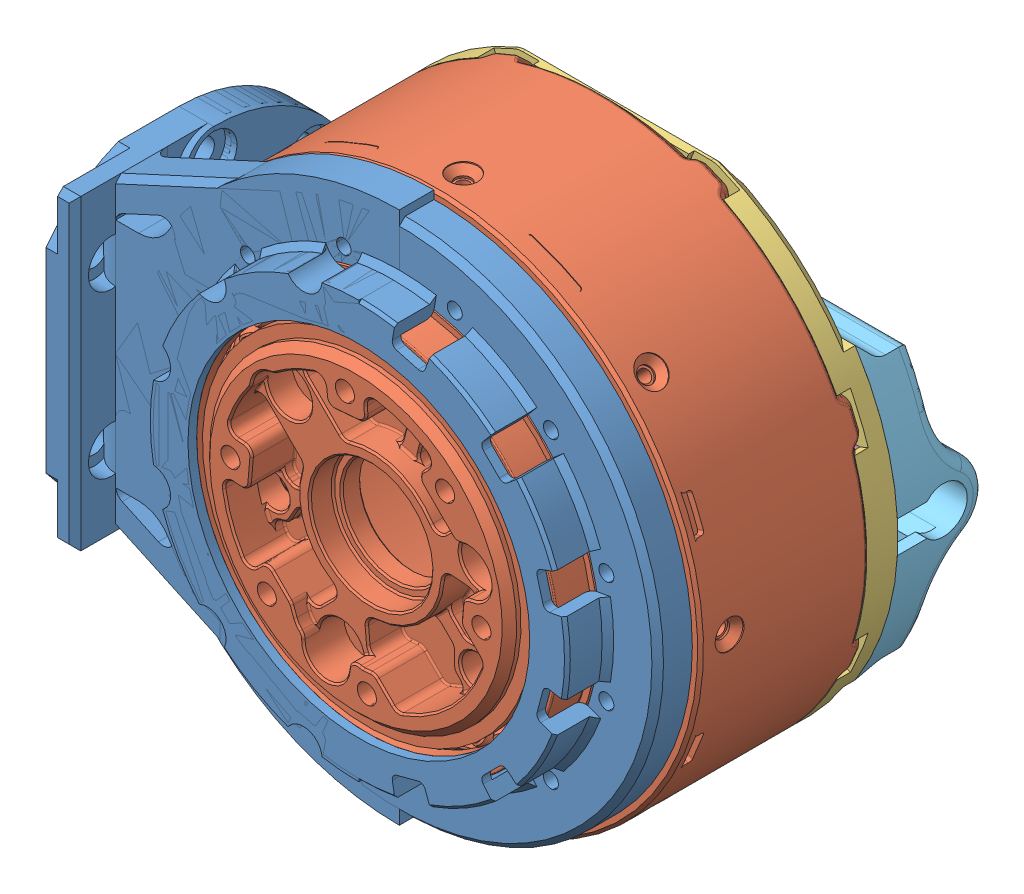
SolidWorks assembly HAA, configuration 默认. Lengths in mm.
Overall size (130.12 130.12 99.91).
5 component instances, 5 part files, 12 mates.
Components (placement in the parent):
- Hip_brace-1: Hip_brace [默认] at (8.6446 4.3873 113.345) size (98.6 92 49.47)
- Power_unit-1: Power_unit [默认] at (8.6446 4.3873 113.835) x (-0.707107 -0.707107 0) z (0 0 1) size (92.01 92.01 49.55)
- 后盖-1: 后盖 [默认] at (8.6446 4.3873 78.785) x (-1 0 0) z (0 0 -1) size (92 85.53 5.65)
- HAA_PCB模板-1: HAA_PCB模板 [默认] at (8.6446 4.3873 74.685) x (0 -1 0) z (0 0 1) size (39 88 1.6)
- 后盖线槽-1: 后盖线槽 [默认] at (8.6446 4.3873 76.285) x (0 -1 0) z (1 0 0) size (59.17 15 92)
Mates (geometry in assembly coordinates):
- 重合2: coincident anti-aligned: plane of Hip_brace-1 through (8.6446 4.3873 121.835) normal (0 0 -1); plane of Power_unit-1 through (31.9791 -18.9472 121.835) normal (0 0 1)
- 同心1: concentric aligned: cylinder of Hip_brace-1 through (44.3838 13.9636 73.865) axis (0 0 1) radius 1.3; cylinder of Power_unit-1 through (44.3838 13.9636 113.335) axis (0 0 1) radius 1.25
- 同心2: concentric aligned: cylinder of Hip_brace-1 through (44.3838 -5.189 73.865) axis (0 0 1) radius 1.3; cylinder of Power_unit-1 through (44.3838 -5.189 113.335) axis (0 0 1) radius 1.25
- 同心7: concentric anti-aligned: cylinder of Power_unit-1 through (-7.6195 43.6522 83.285) axis (0 0 1) radius 1.45; cylinder of 后盖-1 through (-7.6195 43.6522 81.635) axis (0 0 -1) radius 1.85
- 同心8: concentric anti-aligned: cylinder of Power_unit-1 through (24.9086 43.6522 83.285) axis (0 0 1) radius 1.45; cylinder of 后盖-1 through (24.9086 43.6522 81.635) axis (0 0 -1) radius 1.85
- 重合6: coincident anti-aligned: plane of Power_unit-1 through (8.6446 4.3873 78.785) normal (0 0 -1); plane of 后盖-1 through (8.6446 4.3873 78.785) normal (0 0 1)
- 同心9: concentric aligned: cylinder of 后盖-1 through (-30.6203 20.6514 81.635) axis (0 0 -1) radius 1.85; cylinder of HAA_PCB模板-1 through (-30.6203 20.6514 76.285) axis (0 0 -1) radius 1.8
- 同心10: concentric aligned: cylinder of 后盖-1 through (-30.6203 -11.8767 81.635) axis (0 0 -1) radius 1.85; cylinder of HAA_PCB模板-1 through (-30.6203 -11.8767 76.285) axis (0 0 -1) radius 1.8
- 重合8: coincident anti-aligned: plane of 后盖-1 through (8.6446 4.3873 76.285) normal (0 0 -1); plane of HAA_PCB模板-1 through (-30.6203 -11.8767 76.285) normal (0 0 1)
- 同心11: concentric aligned: cylinder of 后盖-1 through (8.6446 4.3873 76.285) axis (0 0 1) radius 46; cylinder of 后盖线槽-1 through (8.6446 4.3873 70.285) axis (0 0 1) radius 46
- 平行1: parallel anti-aligned: plane of HAA_PCB模板-1 through (8.6446 -15.1127 76.285) normal (0 -1 0); plane of 后盖线槽-1 through (8.6446 26.8873 70.285) normal (0 1 0)
- 重合11: coincident anti-aligned: plane of 后盖-1 through (8.6446 4.3873 76.285) normal (0 0 -1); plane of 后盖线槽-1 through (8.6446 4.3873 76.285) normal (0 0 1)
